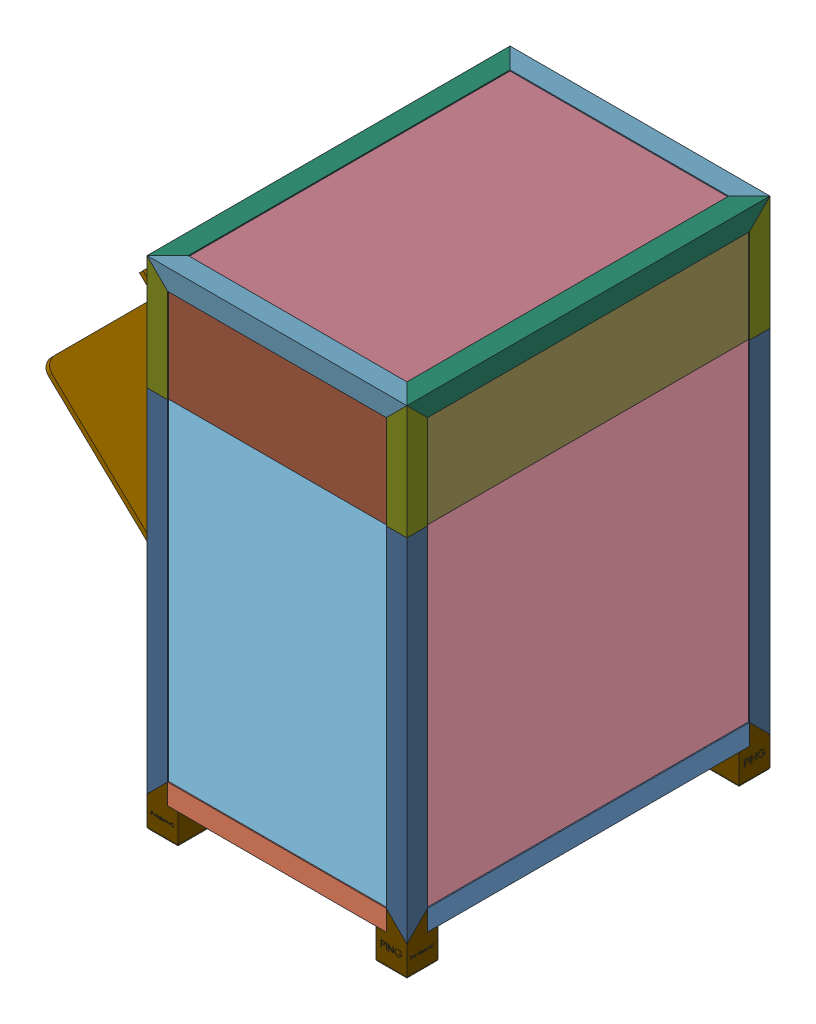
SolidWorks assembly carcasse, configuration Défaut. Lengths in mm.
Overall size (850.58 964 704).
62 component instances, 20 part files, 73 mates.
Components (placement in the parent):
- cadre_600x300mm-1: cadre_600x300mm [Défaut] at (-215.194 -19.8636 -400) size (480 40 680)
  - prof_40x40x600mm-1: prof_40x40x600mm [Défaut] at (-14.8937 4.0689 600) size (40 40 600)
  - Rexroth-Default-1: Rexroth-Default [Default] at (-14.8937 24.0689 720) x (0 -1 0) z (-1 0 0) size (40 40 40)
  - prof_40x40x600mm-3: prof_40x40x600mm [Défaut] at (425.1063 4.0689 600) size (40 40 600)
  - Rexroth-Default-3: Rexroth-Default [Default] at (-14.8937 24.0689 80) x (0 -1 0) z (0 0 -1) size (40 40 40)
  - Rexroth-Default-4: Rexroth-Default [Default] at (425.1063 24.0689 80) x (0 -1 0) z (1 0 0) size (40 40 40)
  - Rexroth-Default-5: Rexroth-Default [Default] at (425.1063 24.0689 720) x (0 -1 0) z (0 0 1) size (40 40 40)
  - prof_40x40x300mm-1: prof_40x40x300mm [Défaut] at (105.1063 4.0689 720) x (0 0 1) z (-1 0 0) size (40 40 400)
  - prof_40x40x300mm-2: prof_40x40x300mm [Défaut] at (105.1063 4.0689 80) x (0 0 1) z (-1 0 0) size (40 40 400)
- prof_40x40x600mm-1: prof_40x40x600mm [Défaut] at (209.9123 104.2053 -320) x (1 0 0) z (0 -1 0) size (40 40 600)
- prof_40x40x600mm-2: prof_40x40x600mm [Défaut] at (209.9123 104.2053 320) x (1 0 0) z (0 -1 0) size (40 40 600)
- prof_40x40x600mm-3: prof_40x40x600mm [Défaut] at (-230.0877 104.2053 320) x (1 0 0) z (0 -1 0) size (40 40 600)
- prof_40x40x600mm-4: prof_40x40x600mm [Défaut] at (-230.0877 104.2053 -320) x (1 0 0) z (0 -1 0) size (40 40 600)
- cadre_600x300mm-2: cadre_600x300mm [Défaut] at (195.0186 628.2742 -400) x (-1 0 0) z (0 0 1) size (480 40 680)
  - prof_40x40x600mm-1: prof_40x40x600mm [Défaut] at (-14.8937 4.0689 600) size (40 40 600)
  - Rexroth-Default-1: Rexroth-Default [Default] at (-14.8937 24.0689 720) x (0 -1 0) z (-1 0 0) size (40 40 40)
  - prof_40x40x600mm-3: prof_40x40x600mm [Défaut] at (425.1063 4.0689 600) size (40 40 600)
  - Rexroth-Default-3: Rexroth-Default [Default] at (-14.8937 24.0689 80) x (0 -1 0) z (0 0 -1) size (40 40 40)
  - Rexroth-Default-4: Rexroth-Default [Default] at (425.1063 24.0689 80) x (0 -1 0) z (1 0 0) size (40 40 40)
  - Rexroth-Default-5: Rexroth-Default [Default] at (425.1063 24.0689 720) x (0 -1 0) z (0 0 1) size (40 40 40)
  - prof_40x40x300mm-1: prof_40x40x300mm [Défaut] at (105.1063 4.0689 720) x (0 0 1) z (-1 0 0) size (40 40 400)
  - prof_40x40x300mm-2: prof_40x40x300mm [Défaut] at (105.1063 4.0689 80) x (0 0 1) z (-1 0 0) size (40 40 400)
- plaque_acrylique_680x670-2: plaque_acrylique_680x670 [Défaut] at (229.9123 299.2053 0) x (0 0 -1) z (1 0 0) size (680 670 10)
- plaque_acrylique_380x670-1: plaque_acrylique_380x670 [Défaut] at (39.9123 299.2053 -350) size (480 670 10)
- plaque_acrylique_380x670-2: plaque_acrylique_380x670 [Défaut] at (39.9123 299.2053 340) size (480 670 10)
- plaque_acrylique_680x670_porte-1: plaque_acrylique_680x670_porte [Défaut] at (-260.0877 299.2053 0) x (0 0 -1) z (1 0 0) size (680 670 10)
- charniere-1: charniere [Défaut] at (-253.7309 154.2053 256.2875) x (0 0 1) z (0 -1 0) size (40 29.08 53.23)
  - axe charnière-1: axe charnière [Défaut] at (-76.2875 9.8568 0) size (40 5 5)
  - batant charnière-1: batant charnière [Défaut] at (-76.2875 10.1991 -17.6196) size (40 7 33.5)
  - batant charnière-2: batant charnière [Défaut] at (-36.2875 -2.6626 12.4029) x (-1 0 0) z (0 0.723942 -0.689861) size (40 7 33.5)
- charniere-2: charniere [Défaut] at (-253.7309 154.2053 -143.7125) x (0 0 1) z (0 -1 0) size (40 29.08 53.23)
  - axe charnière-1: axe charnière [Défaut] at (-76.2875 9.8568 0) size (40 5 5)
  - batant charnière-1: batant charnière [Défaut] at (-76.2875 10.1991 -17.6196) size (40 7 33.5)
  - batant charnière-2: batant charnière [Défaut] at (-36.2875 -2.6626 12.4029) x (-1 0 0) z (0 0.723942 -0.689861) size (40 7 33.5)
- porte-1: porte [Défaut] at (-366.1448 256.769 0) x (0 0 -1) z (0.689861 0.723942 0) size (480 480 10)
- eclisse_40x40x670_bisote_x1-1: eclisse_40x40x670_bisote_x1 [Défaut] at (-242.0877 -47.7947 -331.8864) size (40 682 40)
- eclisse_40x40x670_bisote_x1-2: eclisse_40x40x670_bisote_x1 [Défaut] at (-241.9741 -47.7947 332) x (0 0 -1) z (1 0 0) size (40 682 40)
- eclisse_40x40x670_bisote_x1-3: eclisse_40x40x670_bisote_x1 [Défaut] at (221.9123 -47.7947 331.8864) x (-1 0 0) z (0 0 -1) size (40 682 40)
- eclisse_40x40x670_bisote_x1-4: eclisse_40x40x670_bisote_x1 [Défaut] at (221.7986 -47.7947 -332) x (0 0 1) z (-1 0 0) size (40 682 40)
- couvercle-1: couvercle [Défaut] at (227.4119 747.9268 345) size (504 222 704)
  - plaque_acrylique_380x210-1: plaque_acrylique_380x210 [Défaut] at (-187.4996 -8.7215 -5) size (480 210 10)
  - plaque_acrylique_680x210-1: plaque_acrylique_680x210 [Défaut] at (2.5004 -8.7215 -345) x (0 0 -1) z (1 0 0) size (680 210 10)
  - plaque_acrylique_680x210-2: plaque_acrylique_680x210 [Défaut] at (-487.4996 -8.7215 -345) x (0 0 -1) z (1 0 0) size (680 210 10)
  - plaque_acrylique_380x210-2: plaque_acrylique_380x210 [Défaut] at (-187.4996 -8.7215 -695) size (480 210 10)
  - plaque_acrylique_380x680-1: plaque_acrylique_380x680 [Défaut] at (-187.4996 96.2785 -345) x (1 0 0) z (0 1 0) size (480 680 10)
  - eclisse_40x40x404_bisote_x2-1: eclisse_40x40x404_bisote_x2 [Défaut] at (14.5004 88.1649 -677) x (0 0 1) z (0 -1 0) size (40 504 40)
  - eclisse_40x40x704_bisote_x2-1: eclisse_40x40x704_bisote_x2 [Défaut] at (-5.6132 88.2785 -697) x (0 -1 0) z (-1 0 0) size (40 704 40)
  - eclisse_40x40x404_bisote_x2-2: eclisse_40x40x404_bisote_x2 [Défaut] at (-489.4996 88.1649 -13) x (0 0 -1) z (0 -1 0) size (40 504 40)
  - eclisse_40x40x704_bisote_x2-2: eclisse_40x40x704_bisote_x2 [Défaut] at (-469.4996 88.1649 -697) x (1 0 0) z (0 -1 0) size (40 704 40)
  - eclisse_40x40x222_bisote_x1-1: eclisse_40x40x222_bisote_x1 [Défaut] at (-469.386 108.2785 -677) x (0 0 1) z (1 0 0) size (40 222 40)
  - eclisse_40x40x222_bisote_x1-2: eclisse_40x40x222_bisote_x1 [Défaut] at (-5.4996 108.2785 -676.8864) x (-1 0 0) z (0 0 1) size (40 222 40)
  - eclisse_40x40x222_bisote_x1-3: eclisse_40x40x222_bisote_x1 [Défaut] at (-5.6132 108.2785 -13) x (0 0 -1) z (-1 0 0) size (40 222 40)
  - eclisse_40x40x222_bisote_x1-4: eclisse_40x40x222_bisote_x1 [Défaut] at (-469.4996 108.2785 -13.1136) x (1 0 0) z (0 0 -1) size (40 222 40)
- plaque_acrylique_bas_380x680-1: plaque_acrylique_bas_380x680 [Défaut] at (39.9123 -35.7947 0) x (1 0 0) z (0 -1 0) size (480 680 10)
- Pied-1: Pied [Défaut] at (181.9123 -47.7947 -292) x (-1 0 0) z (0 -1 0) size (60 60 100)
- eclisse_bas_40x40x704-1: eclisse_bas_40x40x704 [Défaut] at (221.9123 -27.681 -312) x (-1 0 0) z (0 1 0) size (40 624 40)
- Pied-2: Pied [Défaut] at (181.9123 -47.7947 292) x (0 0 -1) z (0 -1 0) size (60 60 100)
- Pied-3: Pied [Défaut] at (-202.0877 -47.7947 292) x (1 0 0) z (0 -1 0) size (60 60 100)
- Pied-4: Pied [Défaut] at (-202.0877 -47.7947 -292) x (0 0 1) z (0 -1 0) size (60 60 100)
- eclisse_bas_40x40x704-2: eclisse_bas_40x40x704 [Défaut] at (-242.0877 -27.681 312) x (1 0 0) z (0 1 0) size (40 624 40)
- eclisse_bas_40x40x404-1: eclisse_bas_40x40x404 [Défaut] at (-222.0877 -27.681 -332) x (0 0 1) z (0 1 0) size (40 424 40)
- eclisse_bas_40x40x404-2: eclisse_bas_40x40x404 [Défaut] at (201.9123 -27.681 332) x (0 0 -1) z (0 1 0) size (40 424 40)
Mates (geometry in assembly coordinates):
- Coïncidente1: coincident anti-aligned: plane of cadre_600x300mm-1/Rexroth-Default-3 through (-230.0877 4.2053 -320) normal (0 1 0); plane of prof_40x40x600mm-4 through (-213.0877 4.2053 -337) normal (0 -1 0)
- Coïncidente2: coincident anti-aligned: plane of cadre_600x300mm-1/Rexroth-Default-1 through (-230.0877 4.2053 320) normal (0 1 0); plane of prof_40x40x600mm-3 through (-213.0877 4.2053 303) normal (0 -1 0)
- Coïncidente3: coincident anti-aligned: plane of cadre_600x300mm-1/Rexroth-Default-5 through (209.9123 4.2053 320) normal (0 1 0); plane of prof_40x40x600mm-2 through (226.9123 4.2053 303) normal (0 -1 0)
- Coïncidente4: coincident anti-aligned: plane of cadre_600x300mm-1/Rexroth-Default-4 through (209.9123 4.2053 -320) normal (0 1 0); plane of prof_40x40x600mm-1 through (226.9123 4.2053 -337) normal (0 -1 0)
- Coïncidente5: coincident aligned: plane of cadre_600x300mm-1/Rexroth-Default-4 through (229.9123 -15.7947 -320) normal (1 0 0); plane of prof_40x40x600mm-1 through (229.9123 604.2053 -314) normal (1 0 0)
- Coïncidente6: coincident aligned: plane of cadre_600x300mm-1/Rexroth-Default-4 through (209.9123 -15.7947 -340) normal (0 0 -1); plane of prof_40x40x600mm-1 through (215.9123 604.2053 -340) normal (0 0 -1)
- Coïncidente7: coincident aligned: plane of cadre_600x300mm-1/Rexroth-Default-5 through (229.9123 -15.7947 320) normal (1 0 0); plane of prof_40x40x600mm-2 through (229.9123 604.2053 303) normal (1 0 0)
- Coïncidente8: coincident aligned: plane of cadre_600x300mm-1/Rexroth-Default-5 through (209.9123 -15.7947 340) normal (0 0 1); plane of prof_40x40x600mm-2 through (226.9123 604.2053 340) normal (0 0 1)
- Coïncidente9: coincident aligned: plane of cadre_600x300mm-1/Rexroth-Default-1 through (-230.0877 -15.7947 340) normal (0 0 1); plane of prof_40x40x600mm-3 through (-213.0877 604.2053 340) normal (0 0 1)
- Coïncidente10: coincident aligned: plane of cadre_600x300mm-1/Rexroth-Default-1 through (-250.0877 -15.7947 320) normal (-1 0 0); plane of prof_40x40x600mm-3 through (-250.0877 604.2053 337) normal (-1 0 0)
- Coïncidente11: coincident aligned: plane of cadre_600x300mm-1/Rexroth-Default-3 through (-250.0877 -15.7947 -320) normal (-1 0 0); plane of prof_40x40x600mm-4 through (-250.0877 604.2053 -303) normal (-1 0 0)
- Coïncidente12: coincident aligned: plane of cadre_600x300mm-1/Rexroth-Default-3 through (-230.0877 -15.7947 -340) normal (0 0 -1); plane of prof_40x40x600mm-4 through (-247.0877 604.2053 -340) normal (0 0 -1)
- Coïncidente13: coincident anti-aligned: plane of prof_40x40x600mm-1 through (226.9123 604.2053 -337) normal (0 1 0); plane of cadre_600x300mm-2/Rexroth-Default-3 through (209.9123 604.2053 -320) normal (0 -1 0)
- Coïncidente14: coincident aligned: plane of prof_40x40x600mm-3 through (-250.0877 604.2053 337) normal (-1 0 0); plane of cadre_600x300mm-2/Rexroth-Default-5 through (-250.0877 624.2053 320) normal (-1 0 0)
- Coïncidente15: coincident aligned: plane of prof_40x40x600mm-3 through (-236.0877 604.2053 340) normal (0 0 1); plane of cadre_600x300mm-2/Rexroth-Default-5 through (-230.0877 624.2053 340) normal (0 0 1)
- Coïncidente38: coincident anti-aligned: plane of cadre_600x300mm-2/prof_40x40x600mm-1 through (229.9123 630.2053 -300) normal (1 0 0); plane of plaque_acrylique_680x670-2 through (229.9123 299.2053 0) normal (-1 0 0)
- Coïncidente39: coincident aligned: plane of prof_40x40x600mm-2 through (226.9123 604.2053 340) normal (0 0 1); plane of plaque_acrylique_680x670-2 through (239.9123 634.2053 340) normal (0 0 1)
- Coïncidente40: coincident aligned: plane of cadre_600x300mm-1/prof_40x40x600mm-3 through (215.9123 -35.7947 -300) normal (0 -1 0); plane of plaque_acrylique_680x670-2 through (239.9123 -35.7947 340) normal (0 -1 0)
- Coïncidente41: coincident anti-aligned: plane of prof_40x40x600mm-3 through (-213.0877 604.2053 340) normal (0 0 1); plane of plaque_acrylique_380x670-2 through (39.9123 299.2053 340) normal (0 0 -1)
- Coïncidente42: coincident aligned: plane of cadre_600x300mm-2/Rexroth-Default-5 through (-250.0877 624.2053 320) normal (-1 0 0); plane of plaque_acrylique_380x670-2 through (-250.0877 634.2053 350) normal (-1 0 0)
- Coïncidente43: coincident aligned: plane of cadre_600x300mm-1/prof_40x40x300mm-1 through (189.9123 -35.7947 326) normal (0 -1 0); plane of plaque_acrylique_380x670-2 through (-250.0877 -35.7947 350) normal (0 -1 0)
- Coïncidente44: coincident aligned: plane of cadre_600x300mm-1/prof_40x40x300mm-2 through (189.9123 -35.7947 -337) normal (0 -1 0); plane of plaque_acrylique_380x670-1 through (-250.0877 -35.7947 -340) normal (0 -1 0)
- Coïncidente45: coincident aligned: plane of cadre_600x300mm-2/Rexroth-Default-4 through (-250.0877 624.2053 -320) normal (-1 0 0); plane of plaque_acrylique_380x670-1 through (-250.0877 634.2053 -340) normal (-1 0 0)
- Coïncidente46: coincident anti-aligned: plane of prof_40x40x600mm-4 through (-247.0877 604.2053 -340) normal (0 0 -1); plane of plaque_acrylique_380x670-1 through (39.9123 299.2053 -340) normal (0 0 1)
- Coïncidente48: coincident aligned: plane of cadre_600x300mm-2/Rexroth-Default-5 through (-230.0877 624.2053 340) normal (0 0 1); plane of plaque_acrylique_680x670_porte-1 through (-250.0877 634.2053 340) normal (0 0 1)
- Coïncidente50: coincident anti-aligned: plane of plaque_acrylique_680x670_porte-1 through (-260.0877 299.2053 0) normal (-1 0 0); plane of charniere-1/batant charnière-1 through (-260.0877 114.2053 220) normal (1 0 0)
- Coïncidente51: coincident anti-aligned: plane of plaque_acrylique_680x670_porte-1 through (-260.0877 299.2053 0) normal (-1 0 0); plane of charniere-2/batant charnière-1 through (-260.0877 114.2053 -180) normal (1 0 0)
- Distance4: distance = 20 mm anti-aligned: plane of charniere-2/batant charnière-1 through (-263.5877 154.2053 -220) normal (0 0 -1); plane of plaque_acrylique_680x670_porte-1 through (-260.0877 574.2053 -240) normal (0 0 1)
- Coïncidente54: coincident aligned: line of plaque_acrylique_680x670_porte-1 through (-260.0877 154.2053 220) axis (0 0 -1); line of charniere-2/batant charnière-1 through (-260.0877 154.2053 -180) axis (0 0 -1)
- Distance5: distance = 20 mm anti-aligned: plane of plaque_acrylique_680x670_porte-1 through (-260.0877 574.2053 240) normal (0 0 -1); plane of charniere-1/batant charnière-1 through (-263.5877 154.2053 220) normal (0 0 1)
- Coïncidente57: coincident aligned: line of plaque_acrylique_680x670_porte-1 through (-260.0877 154.2053 220) axis (0 0 -1); line of charniere-1/batant charnière-1 through (-260.0877 154.2053 220) axis (0 0 -1)
- Coïncidente62: coincident anti-aligned: plane of charniere-1/batant charnière-2 through (-290.1309 184.3336 180) normal (0.689861 0.723942 0); plane of porte-1 through (-586.947 467.1766 30) normal (-0.689861 -0.723942 0)
- Coïncidente63: coincident anti-aligned: line of charniere-1/batant charnière-2 through (-261.1732 156.7391 200) axis (0 0 1); line of porte-1 through (-261.1732 156.7391 220) axis (0 0 -1)
- Coïncidente64: coincident anti-aligned: plane of plaque_acrylique_680x670_porte-1 through (-260.0877 574.2053 240) normal (0 0 -1); plane of porte-1 through (-558.3301 453.7202 240) normal (0 0 1)
- Coïncidente65: coincident anti-aligned: plane of plaque_acrylique_380x670-1 through (39.9123 299.2053 -350) normal (0 0 -1); plane of eclisse_40x40x670_bisote_x1-1 through (-260.0877 634.2053 -350) normal (0 0 1)
- Coïncidente66: coincident anti-aligned: plane of plaque_acrylique_680x670_porte-1 through (-260.0877 299.2053 0) normal (-1 0 0); plane of eclisse_40x40x670_bisote_x1-1 through (-260.0877 634.2053 -350) normal (1 0 0)
- Coïncidente67: coincident aligned: plane of plaque_acrylique_680x670_porte-1 through (-250.0877 634.2053 340) normal (0 1 0); plane of eclisse_40x40x670_bisote_x1-1 through (-242.0877 634.2053 -331.8864) normal (0 1 0)
- Coïncidente68: coincident anti-aligned: plane of plaque_acrylique_680x670-2 through (239.9123 299.2053 0) normal (1 0 0); plane of eclisse_40x40x670_bisote_x1-4 through (239.9123 634.2053 -350) normal (-1 0 0)
- Coïncidente69: coincident anti-aligned: plane of plaque_acrylique_380x670-1 through (39.9123 299.2053 -350) normal (0 0 -1); plane of eclisse_40x40x670_bisote_x1-4 through (239.9123 634.2053 -350) normal (0 0 1)
- Coïncidente70: coincident aligned: plane of plaque_acrylique_380x670-1 through (-250.0877 634.2053 -340) normal (0 1 0); plane of eclisse_40x40x670_bisote_x1-4 through (221.7986 634.2053 -332) normal (0 1 0)
- Coïncidente71: coincident anti-aligned: plane of plaque_acrylique_380x670-2 through (39.9123 299.2053 350) normal (0 0 1); plane of eclisse_40x40x670_bisote_x1-2 through (-260.0877 634.2053 350) normal (0 0 -1)
- Coïncidente72: coincident anti-aligned: plane of plaque_acrylique_680x670_porte-1 through (-260.0877 299.2053 0) normal (-1 0 0); plane of eclisse_40x40x670_bisote_x1-2 through (-260.0877 634.2053 350) normal (1 0 0)
- Coïncidente73: coincident aligned: plane of plaque_acrylique_380x670-2 through (-250.0877 634.2053 350) normal (0 1 0); plane of eclisse_40x40x670_bisote_x1-2 through (-241.9741 634.2053 332) normal (0 1 0)
- Coïncidente74: coincident anti-aligned: plane of plaque_acrylique_680x670-2 through (239.9123 299.2053 0) normal (1 0 0); plane of eclisse_40x40x670_bisote_x1-3 through (239.9123 634.2053 350) normal (-1 0 0)
- Coïncidente75: coincident anti-aligned: plane of plaque_acrylique_380x670-2 through (39.9123 299.2053 350) normal (0 0 1); plane of eclisse_40x40x670_bisote_x1-3 through (239.9123 634.2053 350) normal (0 0 -1)
- Coïncidente76: coincident aligned: plane of plaque_acrylique_380x670-2 through (-250.0877 634.2053 350) normal (0 1 0); plane of eclisse_40x40x670_bisote_x1-3 through (221.9123 634.2053 331.8864) normal (0 1 0)
- Coïncidente100: coincident: plane of plaque_acrylique_680x670_porte-1 through (-250.0877 634.2053 340) normal (0 1 0); line of eclisse_40x40x670_bisote_x1-2 through (-260.0877 634.2053 350) axis (0 0 -1)
- Coïncidente101: coincident anti-aligned: plane of prof_40x40x600mm-4 through (-250.0877 604.2053 -326) normal (-1 0 0); plane of plaque_acrylique_680x670_porte-1 through (-250.0877 299.2053 0) normal (1 0 0)
- Coïncidente116: coincident anti-aligned: line of plaque_acrylique_680x670-2 through (239.9123 634.2053 -340) axis (0 0 1); line of couvercle-1/plaque_acrylique_680x210-1 through (239.9123 634.2053 340) axis (0 0 -1)
- Coïncidente117: coincident anti-aligned: line of plaque_acrylique_380x670-1 through (229.9123 634.2053 -350) axis (-1 0 0); line of couvercle-1/plaque_acrylique_380x210-2 through (-250.0877 634.2053 -350) axis (1 0 0)
- Coïncidente118: coincident anti-aligned: plane of cadre_600x300mm-1/prof_40x40x600mm-1 through (-247.0877 -35.7947 -300) normal (0 -1 0); plane of plaque_acrylique_bas_380x680-1 through (39.9123 -35.7947 0) normal (0 1 0)
- Coïncidente119: coincident: plane of cadre_600x300mm-1/prof_40x40x600mm-1 through (-250.0877 -21.7947 -300) normal (-1 0 0); line of plaque_acrylique_bas_380x680-1 through (-250.0877 -35.7947 340) axis (0 0 -1)
- Coïncidente120: coincident: line of cadre_600x300mm-1/prof_40x40x300mm-2 through (189.9123 -32.7947 -340) axis (-1 0 0); plane of plaque_acrylique_bas_380x680-1 through (-250.0877 -45.7947 -340) normal (0 0 -1)
- Coaxiale1: concentric aligned: cylinder of plaque_acrylique_bas_380x680-1 through (209.9123 -35.7947 -320) axis (0 -1 0) radius 12.5; cylinder of Pied-1 through (209.9123 -27.7947 -320) axis (0 -1 0) radius 12
- Coïncidente124: coincident anti-aligned: plane of eclisse_40x40x670_bisote_x1-4 through (-348.0877 -47.7947 -352) normal (0 -0.707107 0.707107); plane of Pied-1 through (239.9123 -7.7947 -312) normal (0 0.707107 -0.707107)
- Coaxiale2: concentric aligned: circle of plaque_acrylique_bas_380x680-1; cylinder of Pied-2 through (209.9123 -27.7947 320) axis (0 -1 0) radius 12
- Coïncidente126: coincident anti-aligned: plane of eclisse_40x40x670_bisote_x1-3 through (241.9123 -47.7947 -238) normal (-0.707107 -0.707107 0); plane of Pied-2 through (201.9123 -7.7947 350) normal (0.707107 0.707107 0)
- Coïncidente127: coincident anti-aligned: plane of plaque_acrylique_680x670-2 through (239.9123 299.2053 0) normal (1 0 0); plane of eclisse_bas_40x40x704-1 through (239.9123 -45.7947 312) normal (-1 0 0)
- Coïncidente128: coincident anti-aligned: plane of plaque_acrylique_bas_380x680-1 through (39.9123 -45.7947 0) normal (0 -1 0); plane of eclisse_bas_40x40x704-1 through (239.9123 -45.7947 312) normal (0 1 0)
- Coïncidente129: coincident anti-aligned: line of Pied-1 through (241.9123 -7.7947 -312) axis (0 -1 0); line of eclisse_bas_40x40x704-1 through (241.9123 -47.7947 -312) axis (0 1 0)
- Coaxiale3: concentric aligned: circle of plaque_acrylique_bas_380x680-1; cylinder of Pied-3 through (-230.0877 -27.7947 320) axis (0 -1 0) radius 12
- Coïncidente130: coincident anti-aligned: plane of eclisse_40x40x670_bisote_x1-2 through (327.9123 -47.7947 352) normal (0 -0.707107 -0.707107); plane of Pied-3 through (-260.0877 -7.7947 312) normal (0 0.707107 0.707107)
- Coaxiale4: concentric aligned: circle of plaque_acrylique_bas_380x680-1; cylinder of Pied-4 through (-230.0877 -27.7947 -320) axis (0 -1 0) radius 12
- Coïncidente131: coincident anti-aligned: plane of eclisse_40x40x670_bisote_x1-1 through (-262.0877 -47.7947 238) normal (0.707107 -0.707107 0); plane of Pied-4 through (-222.0877 -7.7947 -350) normal (-0.707107 0.707107 0)
- Coïncidente132: coincident anti-aligned: plane of plaque_acrylique_680x670_porte-1 through (-260.0877 299.2053 0) normal (-1 0 0); plane of eclisse_bas_40x40x704-2 through (-260.0877 -45.7947 -312) normal (1 0 0)
- Coïncidente133: coincident anti-aligned: plane of plaque_acrylique_bas_380x680-1 through (39.9123 -45.7947 0) normal (0 -1 0); plane of eclisse_bas_40x40x704-2 through (-260.0877 -45.7947 -312) normal (0 1 0)
- Coïncidente134: coincident anti-aligned: line of eclisse_40x40x670_bisote_x1-2 through (-262.0877 634.2053 312) axis (0 -1 0); line of eclisse_bas_40x40x704-2 through (-262.0877 -47.7947 312) axis (0 1 0)
- Coïncidente135: coincident anti-aligned: plane of plaque_acrylique_380x670-1 through (39.9123 299.2053 -350) normal (0 0 -1); plane of eclisse_bas_40x40x404-1 through (201.9123 -45.7947 -350) normal (0 0 1)
- Coïncidente136: coincident anti-aligned: plane of plaque_acrylique_bas_380x680-1 through (39.9123 -45.7947 0) normal (0 -1 0); plane of eclisse_bas_40x40x404-1 through (201.9123 -45.7947 -350) normal (0 1 0)
- Coïncidente137: coincident anti-aligned: line of Pied-1 through (201.9123 -7.7947 -352) axis (0 -1 0); line of eclisse_bas_40x40x404-1 through (201.9123 -47.7947 -352) axis (0 1 0)
- Coïncidente138: coincident anti-aligned: plane of plaque_acrylique_380x670-2 through (39.9123 299.2053 350) normal (0 0 1); plane of eclisse_bas_40x40x404-2 through (-222.0877 -45.7947 350) normal (0 0 -1)
- Coïncidente139: coincident anti-aligned: plane of plaque_acrylique_bas_380x680-1 through (39.9123 -45.7947 0) normal (0 -1 0); plane of eclisse_bas_40x40x404-2 through (-222.0877 -45.7947 350) normal (0 1 0)
- Coïncidente140: coincident anti-aligned: line of Pied-3 through (-222.0877 -7.7947 352) axis (0 -1 0); line of eclisse_bas_40x40x404-2 through (-222.0877 -47.7947 352) axis (0 1 0)
